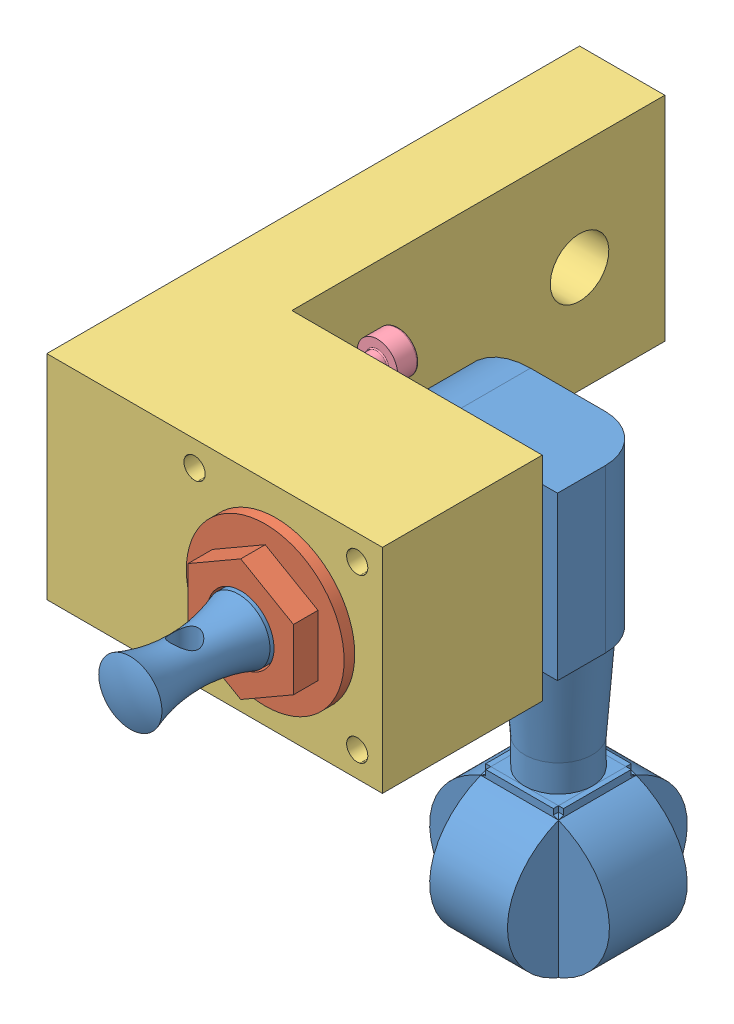
SolidWorks assembly tuning peg tensioner 2, configuration Default. Lengths in mm.
Overall size (36.97 43.44 64.21).
4 component instances, 4 part files, 9 mates.
Components (placement in the parent):
- TUNING PEG-1: TUNING PEG [Default] at origin size (23.09 41.06 42.14)
- TUNING PEG RETAINER-1: TUNING PEG RETAINER [Default] at (0 0 12.74) x (0 1 0) z (0 0 1) size (14.8 14.8 14.45)
- tuning peg mount 2-1: tuning peg mount 2 [Default] at (-5.75 0 23.89) x (1 0 0) z (0 -1 0) size (31.5 50 20)
- M2X10-1: M2X10 [Default] at (-7.6332 7.6332 6.731) x (0 0 1) z (1 0 0) size (12 3.8 3.8)
Mates (geometry in assembly coordinates):
- Concentric116: concentric aligned: cylinder of TUNING PEG-1 through (0 0 8.89) axis (0 0 1) radius 5; cylinder of tuning peg mount 2-1 through (0 0 -6.11) axis (0 0 1) radius 5.08
- Coincident205: coincident anti-aligned: plane of TUNING PEG-1 through (3.8845 0 8.89) normal (0 0 1); plane of tuning peg mount 2-1 through (-5.75 0 8.89) normal (0 0 -1)
- Concentric118: concentric anti-aligned: cylinder of TUNING PEG-1 through (0 0 23.241) axis (0 0 -1) radius 2.95; cylinder of TUNING PEG RETAINER-1 through (0 0 12.74) axis (0 0 1) radius 3.125
- Concentric119: concentric: cylinder of TUNING PEG-1 through (-7.6332 7.6332 8.89) axis (0 0 -1) radius 1.125; cylinder of M2X10-1 through (-7.6332 7.6332 12.2537) axis (0 0 1) radius 1
- Coincident207: coincident: plane of TUNING PEG-1 through (-6.8243 6.8243 6.731) normal (0 0 -1); plane of M2X10-1 through (-7.6332 6.1832 6.731) normal (0 0 1)
- Coincident208: coordinate: point of TUNING PEG-1
- Parallel1: parallel anti-aligned: plane of TUNING PEG RETAINER-1 through (-4.95 -2.8579 27.19) normal (-1 0 0); plane of tuning peg mount 2-1 through (10 -10 8.89) normal (1 0 0)
- Coincident209: coincident anti-aligned: plane of TUNING PEG RETAINER-1 through (0 0 23.89) normal (0 0 -1); plane of tuning peg mount 2-1 through (-5.75 0 23.89) normal (0 0 1)
- Parallel2: parallel aligned: plane of TUNING PEG-1 through (11.43 7.62 0) normal (0 1 0); plane of tuning peg mount 2-1 through (-21.5 10 8.89) normal (0 1 0)
